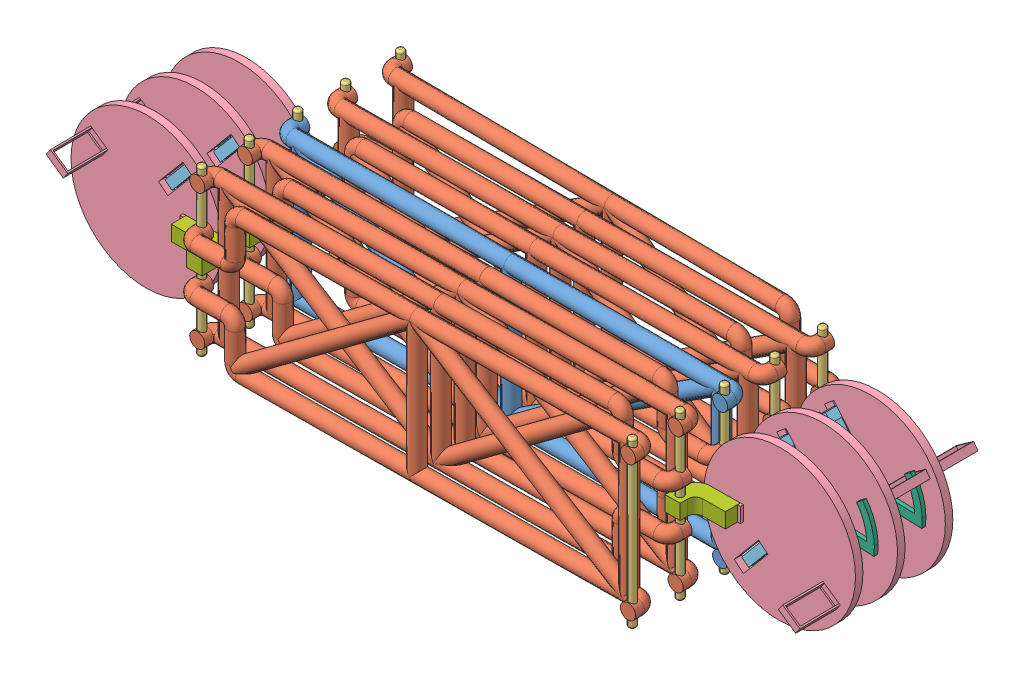
SolidWorks assembly assem3, configuration Default. Lengths in mm.
Overall size (502.87 110 155.14).
49 component instances, 7 part files, 55 mates.
Components (placement in the parent):
- center_frame-1: center_frame [Default] at (106.7449 154.0324 247.9449) size (310 100 22)
- true_frame-1: true_frame [Default] at (106.7528 154.6386 264.0904) x (-1 0 0.00097) z (-0.00097 0 -1) size (310 100 22)
- true_frame-2: true_frame [Default] at (106.7006 154.6386 231.153) x (0.999986 0 -0.00528) z (0.00528 0 0.999986) size (310 100 22)
- true_frame-3: true_frame [Default] at (106.6161 154.9393 215.1532) x (-0.999986 0 0.00528) z (0.00528 0 0.999986) size (310 100 22)
- true_frame-4: true_frame [Default] at (106.8233 154.9393 278.9571) x (0.999964 0 -0.008523) z (-0.008523 0 -0.999964) size (310 100 22)
- hinge_rod-1: hinge_rod [Default] at (256.7449 99.5924 255.9449) x (0.999788 0 -0.020583) z (0.020583 0 0.999788) size (5 110 5)
- hinge_rod-2: hinge_rod [Default] at (256.6563 99.5924 222.361) x (0.596438 0 -0.802659) z (0.802659 0 0.596438) size (5 110 5)
- hinge_rod-3: hinge_rod [Default] at (256.8861 99.5924 285.6784) x (0.825949 0 -0.563745) z (0.563745 0 0.825949) size (5 110 5)
- hinge_rod-4: hinge_rod [Default] at (-43.2394 99.5924 272.2358) x (0.395821 0 -0.918328) z (0.918328 0 0.395821) size (5 110 5)
- hinge_rod-5: hinge_rod [Default] at (-43.2551 99.5924 239.9449) x (0.565106 0 0.825018) z (-0.825018 0 0.565106) size (5 110 5)
- hinge_rod-6: hinge_rod [Default] at (-43.424 99.5924 207.9453) x (-0.435776 0 0.900055) z (-0.900055 0 -0.435776) size (5 110 5)
- Assem4^assem3-1: Assem4^assem3 [Default] at (0 -0.7838 0) size (106.16 100 39.17) (virtual)
  - Cap_base-1: Cap_base [Default] at (307.7348 155.7231 237.0915) x (0.999986 0 -0.00528) z (0.00528 0 0.999986) size (100 100 38)
  - Cap_lid-1: Cap_lid [Default] at (289.162 177.8597 239.4396) x (0.643702 -0.765268 -0.003399) z (-0.765258 -0.643711 0.004041) size (20 9.5 11)
  - Cap_pin-1: Cap_pin [Default] at (307.7902 155.7231 247.5914) x (0.999004 -0.044302 -0.005275) z (0.00528 0 0.999986) size (80 32.64 2.5)
  - lock_arm-1: lock_arm [Default] at (281.7351 160.7231 237.2288) x (-0.00528 0 -0.999986) z (-0.999986 0 0.00528) size (20 10 30)
- Assem4^assem3-2: Assem4^assem3 [Default] at (212.456 -0.7838 495.7011) x (-0.999991 0 -0.00431) z (0.00431 0 -0.999991) size (106.16 100 39.17) (virtual)
  - Cap_base-1: Cap_base [Default] at (307.7348 155.7231 237.0915) x (0.999986 0 -0.00528) z (0.00528 0 0.999986) size (100 100 38)
  - Cap_lid-1: Cap_lid [Default] at (289.162 177.8597 239.4396) x (0.643702 -0.765268 -0.003399) z (-0.765258 -0.643711 0.004041) size (20 9.5 11)
  - Cap_pin-1: Cap_pin [Default] at (307.7902 155.7231 247.5914) x (0.999004 -0.044302 -0.005275) z (0.00528 0 0.999986) size (80 32.64 2.5)
  - lock_arm-1: lock_arm [Default] at (281.7351 160.7231 237.2288) x (-0.00528 0 -0.999986) z (-0.999986 0 0.00528) size (20 10 30)
- true_frame-5: true_frame [Default] at (106.9597 154.6386 294.9565) x (-0.999964 0 0.008523) z (-0.008523 0 -0.999964) size (310 100 22)
- true_frame-6: true_frame [Default] at (107.0961 154.9393 310.956) x (0.999964 0 -0.008523) z (-0.008523 0 -0.999964) size (310 100 22)
- hinge_rod-7: hinge_rod [Default] at (-42.9667 99.5924 304.2347) x (0.864022 0 -0.503454) z (0.503454 0 0.864022) size (5 110 5)
- hinge_rod-8: hinge_rod [Default] at (257.1588 99.5924 317.6773) x (0.395821 0 -0.918328) z (0.918328 0 0.395821) size (5 110 5)
- Assem4^assem3-3: Assem4^assem3 [Default] at (214.4093 -0.7838 525.7623) x (-0.999995 0 0.003243) z (-0.003243 0 -0.999995) size (106.16 100 39.17) (virtual)
  - Cap_base-1: Cap_base [Default] at (307.7348 155.7231 237.0915) x (0.999986 0 -0.00528) z (0.00528 0 0.999986) size (100 100 38)
  - Cap_lid-1: Cap_lid [Default] at (289.162 177.8597 239.4396) x (0.643702 -0.765268 -0.003399) z (-0.765258 -0.643711 0.004041) size (20 9.5 11)
  - Cap_pin-1: Cap_pin [Default] at (307.7902 155.7231 247.5914) x (0.999004 -0.044302 -0.005275) z (0.00528 0 0.999986) size (80 32.64 2.5)
  - lock_arm-1: lock_arm [Default] at (281.7351 160.7231 237.2288) x (-0.00528 0 -0.999986) z (-0.999986 0 0.00528) size (20 10 30)
- Assem4^assem3-5: Assem4^assem3 [Default] at (3.3234 310.3617 511.5608) x (0.999905 0 -0.013803) z (-0.013803 0 -0.999905) size (106.16 100 39.17) (virtual)
  - Cap_base-1: Cap_base [Default] at (307.7348 155.7231 237.0915) x (0.999986 0 -0.00528) z (0.00528 0 0.999986) size (100 100 38)
  - Cap_lid-1: Cap_lid [Default] at (289.162 177.8597 239.4396) x (0.643702 -0.765268 -0.003399) z (-0.765258 -0.643711 0.004041) size (20 9.5 11)
  - Cap_pin-1: Cap_pin [Default] at (307.7902 155.7231 247.5914) x (0.999004 -0.044302 -0.005275) z (0.00528 0 0.999986) size (80 32.64 2.5)
  - lock_arm-1: lock_arm [Default] at (281.7351 160.7231 237.2288) x (-0.00528 0 -0.999986) z (-0.999986 0 0.00528) size (20 10 30)
- true_frame-7: true_frame [Default] at (106.5316 154.6386 199.1534) x (0.999986 0 -0.00528) z (0.00528 0 0.999986) size (310 100 22)
- true_frame-8: true_frame [Default] at (106.5712 154.9393 180.919) x (-0.999954 0 -0.009619) z (-0.009619 0 0.999954) size (310 100 22)
- hinge_rod-9: hinge_rod [Default] at (256.4873 99.5924 190.3615) x (-0.435776 0 0.900055) z (-0.900055 0 -0.435776) size (5 110 5)
- Assem4^assem3-6: Assem4^assem3 [Default] at (-0.169 -0.7837 -31.9996) size (106.16 100 39.17) (virtual)
  - Cap_base-1: Cap_base [Default] at (307.7348 155.7231 237.0915) x (0.999986 0 -0.00528) z (0.00528 0 0.999986) size (100 100 38)
  - Cap_lid-1: Cap_lid [Default] at (289.162 177.8597 239.4396) x (0.643702 -0.765268 -0.003399) z (-0.765258 -0.643711 0.004041) size (20 9.5 11)
  - Cap_pin-1: Cap_pin [Default] at (307.7902 155.7231 247.5914) x (0.999004 -0.044302 -0.005275) z (0.00528 0 0.999986) size (80 32.64 2.5)
  - lock_arm-1: lock_arm [Default] at (281.7351 160.7231 237.2288) x (-0.00528 0 -0.999986) z (-0.999986 0 0.00528) size (20 10 30)
- Assem4^assem3-7: Assem4^assem3 [Default] at (210.8697 310.3617 -17.1137) x (-0.999944 0 0.01056) z (0.01056 0 0.999944) size (106.16 100 39.17) (virtual)
  - Cap_base-1: Cap_base [Default] at (307.7348 155.7231 237.0915) x (0.999986 0 -0.00528) z (0.00528 0 0.999986) size (100 100 38)
  - Cap_lid-1: Cap_lid [Default] at (289.162 177.8597 239.4396) x (0.643702 -0.765268 -0.003399) z (-0.765258 -0.643711 0.004041) size (20 9.5 11)
  - Cap_pin-1: Cap_pin [Default] at (307.7902 155.7231 247.5914) x (0.999004 -0.044302 -0.005275) z (0.00528 0 0.999986) size (80 32.64 2.5)
  - lock_arm-1: lock_arm [Default] at (281.7351 160.7231 237.2288) x (-0.00528 0 -0.999986) z (-0.999986 0 0.00528) size (20 10 30)
- hinge_rod-10: hinge_rod [Default] at (-43.3449 99.5924 171.4765) x (-0.435776 0 0.900055) z (-0.900055 0 -0.435776) size (5 110 5)
Mates (geometry in assembly coordinates):
- Concentric1: concentric aligned: cylinder of center_frame-1 through (256.7449 104.0324 255.9449) axis (0 1 0) radius 2.5; cylinder of true_frame-1 through (256.7449 104.6386 255.9449) axis (0 1 0) radius 2.5
- Distance1: distance = 30 mm: point of center_frame-1; point of true_frame-1
- Concentric2: concentric aligned: cylinder of center_frame-1 through (-43.2551 104.0324 239.9449) axis (0 1 0) radius 2.5; cylinder of true_frame-2 through (-43.2551 104.6386 239.9449) axis (0 1 0) radius 2.5
- Distance3: distance = 30 mm: point of center_frame-1; point of true_frame-2
- Concentric3: concentric anti-aligned: cylinder of true_frame-2 through (256.6563 104.6386 222.361) axis (0 1 0) radius 2.5; cylinder of true_frame-3 through (256.6563 204.9393 222.361) axis (0 -1 0) radius 2.5
- Distance4: distance = 60 mm: point of true_frame-3; point of true_frame-2
- Concentric4: concentric anti-aligned: cylinder of true_frame-1 through (-43.2394 104.6386 272.2358) axis (0 1 0) radius 2.5; cylinder of true_frame-4 through (-43.2394 204.9393 272.2358) axis (0 -1 0) radius 2.5
- Distance5: distance = 60 mm: point of true_frame-1; point of true_frame-4
- Concentric5: concentric anti-aligned: cylinder of center_frame-1 through (256.7449 104.0324 255.9449) axis (0 1 0) radius 2.5; cylinder of hinge_rod-1 through (256.7449 209.5924 255.9449) axis (0 -1 0) radius 2.5
- Concentric6: concentric aligned: cylinder of true_frame-3 through (256.6563 204.9393 222.361) axis (0 -1 0) radius 2.5; cylinder of hinge_rod-2 through (256.6563 209.5924 222.361) axis (0 -1 0) radius 2.5
- Coincident7: coincident aligned: plane of hinge_rod-1 through (256.7449 209.5924 255.9449) normal (0 1 0); plane of hinge_rod-2 through (256.6563 209.5924 222.361) normal (0 1 0)
- Concentric7: concentric aligned: cylinder of true_frame-4 through (256.8861 204.9393 285.6784) axis (0 -1 0) radius 2.5; cylinder of hinge_rod-3 through (256.8861 209.5924 285.6784) axis (0 -1 0) radius 2.5
- Coincident8: coincident aligned: plane of hinge_rod-3 through (256.8861 209.5924 285.6784) normal (0 1 0); plane of hinge_rod-1 through (256.7449 209.5924 255.9449) normal (0 1 0)
- Coincident9: coincident aligned: plane of hinge_rod-3 through (256.8861 209.5924 285.6784) normal (0 1 0); plane of hinge_rod-2 through (256.6563 209.5924 222.361) normal (0 1 0)
- Concentric8: concentric aligned: cylinder of true_frame-4 through (-43.2394 204.9393 272.2358) axis (0 -1 0) radius 2.5; cylinder of hinge_rod-4 through (-43.2394 209.5924 272.2358) axis (0 -1 0) radius 2.5
- Concentric9: concentric anti-aligned: cylinder of true_frame-2 through (-43.2551 104.6386 239.9449) axis (0 1 0) radius 2.5; cylinder of hinge_rod-5 through (-43.2551 209.5924 239.9449) axis (0 -1 0) radius 2.5
- Concentric10: concentric aligned: cylinder of true_frame-3 through (-43.424 204.9393 207.9453) axis (0 -1 0) radius 2.5; cylinder of hinge_rod-6 through (-43.424 209.5924 207.9453) axis (0 -1 0) radius 2.5
- Coincident14: coincident aligned: plane of hinge_rod-6 through (-43.424 209.5924 207.9453) normal (0 1 0); plane of hinge_rod-5 through (-43.2551 209.5924 239.9449) normal (0 1 0)
- Coincident15: coincident aligned: plane of hinge_rod-6 through (-43.424 209.5924 207.9453) normal (0 1 0); plane of hinge_rod-4 through (-43.2394 209.5924 272.2358) normal (0 1 0)
- Coincident16: coincident aligned: plane of hinge_rod-6 through (-43.424 209.5924 207.9453) normal (0 1 0); plane of hinge_rod-2 through (256.6563 209.5924 222.361) normal (0 1 0)
- Coincident17: coincident aligned: plane of hinge_rod-6 through (-43.424 209.5924 207.9453) normal (0 1 0); plane of hinge_rod-1 through (256.7449 209.5924 255.9449) normal (0 1 0)
- Coincident18: coincident aligned: plane of hinge_rod-6 through (-43.424 209.5924 207.9453) normal (0 1 0); plane of hinge_rod-3 through (256.8861 209.5924 285.6784) normal (0 1 0)
- Concentric20: concentric aligned: cylinder of hinge_rod-2 through (256.6563 209.5924 222.361) axis (0 -1 0) radius 2.5; cylinder of Assem4^assem3-1/lock_arm-1 through (256.6563 159.9393 222.361) axis (0 -1 0) radius 2.5
- Parallel8: parallel aligned: plane of true_frame-2 through (256.6404 109.6386 219.3611) normal (-0.00528 0 -0.999986); plane of Assem4^assem3-1/lock_arm-1 through (281.6295 149.9393 217.2291) normal (-0.00528 0 -0.999986)
- Distance12: distance = 17 mm: point of true_frame-3; point of Assem4^assem3-1/lock_arm-1
- Concentric21: concentric aligned: cylinder of hinge_rod-4 through (-43.2394 209.5924 272.2358) axis (0 -1 0) radius 2.5; cylinder of Assem4^assem3-2/lock_arm-1 through (-43.2394 159.9393 272.2358) axis (0 -1 0) radius 2.5
- Parallel9: parallel aligned: plane of true_frame-1 through (-43.2365 199.6386 275.2358) normal (0.00097 0 1); plane of Assem4^assem3-2/lock_arm-1 through (-68.2345 149.9393 277.2601) normal (0.00097 0 1)
- Distance13: distance = 17 mm: point of true_frame-4; point of Assem4^assem3-2/lock_arm-1
- Concentric22: concentric anti-aligned: cylinder of hinge_rod-3 through (256.8861 209.5924 285.6784) axis (0 -1 0) radius 2.5; cylinder of true_frame-5 through (256.8861 104.6386 285.6784) axis (0 1 0) radius 2.5
- Distance14: distance = 60 mm: point of true_frame-5; point of true_frame-4
- Concentric23: concentric anti-aligned: cylinder of true_frame-5 through (-42.9667 104.6386 304.2347) axis (0 1 0) radius 2.5; cylinder of hinge_rod-7 through (-42.9667 209.5924 304.2347) axis (0 -1 0) radius 2.5
- Concentric24: concentric aligned: cylinder of true_frame-6 through (-42.9667 204.9393 304.2347) axis (0 -1 0) radius 2.5; cylinder of hinge_rod-7 through (-42.9667 209.5924 304.2347) axis (0 -1 0) radius 2.5
- Coincident33: coincident aligned: plane of hinge_rod-4 through (-43.2394 209.5924 272.2358) normal (0 1 0); plane of hinge_rod-7 through (-42.9667 209.5924 304.2347) normal (0 1 0)
- Distance15: distance = 60 mm: point of true_frame-5; point of true_frame-6
- Concentric25: concentric aligned: cylinder of true_frame-6 through (257.1588 204.9393 317.6773) axis (0 -1 0) radius 2.5; cylinder of hinge_rod-8 through (257.1588 209.5924 317.6773) axis (0 -1 0) radius 2.5
- Coincident34: coincident aligned: plane of hinge_rod-3 through (256.8861 209.5924 285.6784) normal (0 1 0); plane of hinge_rod-8 through (257.1588 209.5924 317.6773) normal (0 1 0)
- Concentric26: concentric aligned: cylinder of hinge_rod-7 through (-42.9667 209.5924 304.2347) axis (0 -1 0) radius 2.5; cylinder of Assem4^assem3-3/lock_arm-1 through (-42.9667 159.9393 304.2347) axis (0 -1 0) radius 2.5
- Distance17: distance = 17 mm: point of true_frame-6; point of Assem4^assem3-3/lock_arm-1
- Parallel10: parallel aligned: plane of true_frame-5 through (-42.9411 199.6386 307.2346) normal (0.008523 0 0.999964); plane of Assem4^assem3-3/lock_arm-1 through (-67.9231 149.9393 309.4476) normal (0.008523 0 0.999964)
- Concentric28: concentric anti-aligned: cylinder of hinge_rod-3 through (256.8861 209.5924 285.6784) axis (0 -1 0) radius 2.5; cylinder of Assem4^assem3-5/lock_arm-1 through (256.8861 149.6386 285.6784) axis (0 1 0) radius 2.5
- Parallel11: parallel aligned: plane of true_frame-4 through (256.9116 199.9393 288.6783) normal (0.008523 0 0.999964); plane of Assem4^assem3-5/lock_arm-1 through (281.9278 159.6386 290.4652) normal (0.008523 0 0.999964)
- Distance18: distance = 17 mm: point of Assem4^assem3-5/lock_arm-1; point of true_frame-5
- Concentric29: concentric anti-aligned: cylinder of hinge_rod-6 through (-43.424 209.5924 207.9453) axis (0 -1 0) radius 2.5; cylinder of true_frame-7 through (-43.424 104.6386 207.9453) axis (0 1 0) radius 2.5
- Concentric30: concentric anti-aligned: cylinder of true_frame-7 through (256.4873 104.6386 190.3615) axis (0 1 0) radius 2.5; cylinder of hinge_rod-9 through (256.4873 209.5924 190.3615) axis (0 -1 0) radius 2.5
- Concentric31: concentric aligned: cylinder of true_frame-8 through (256.4873 204.9393 190.3615) axis (0 -1 0) radius 2.5; cylinder of hinge_rod-9 through (256.4873 209.5924 190.3615) axis (0 -1 0) radius 2.5
- Distance19: distance = 60 mm: point of true_frame-7; point of true_frame-3
- Coincident37: coincident aligned: circle of hinge_rod-2; plane of hinge_rod-9 through (256.4873 209.5924 190.3615) normal (0 1 0)
- Concentric33: concentric aligned: cylinder of hinge_rod-9 through (256.4873 209.5924 190.3615) axis (0 -1 0) radius 2.5; cylinder of Assem4^assem3-6/lock_arm-1 through (256.4873 159.9394 190.3615) axis (0 -1 0) radius 2.5
- Distance22: distance = 17 mm: point of Assem4^assem3-6/lock_arm-1; point of true_frame-8
- Distance23: distance = 60 mm: point of true_frame-8; point of true_frame-7
- Concentric34: concentric anti-aligned: cylinder of hinge_rod-6 through (-43.424 209.5924 207.9453) axis (0 -1 0) radius 2.5; cylinder of Assem4^assem3-7/lock_arm-1 through (-43.424 149.6386 207.9453) axis (0 1 0) radius 2.5
- Parallel12: parallel aligned: plane of true_frame-3 through (-43.4399 199.9393 204.9454) normal (-0.00528 0 -0.999986); plane of Assem4^assem3-7/lock_arm-1 through (-68.4501 159.6386 203.0774) normal (-0.00528 0 -0.999986)
- Distance25: distance = 17 mm: point of Assem4^assem3-7/lock_arm-1; point of true_frame-7
- Concentric35: concentric aligned: cylinder of true_frame-8 through (-43.3449 204.9393 171.4765) axis (0 -1 0) radius 2.5; cylinder of hinge_rod-10 through (-43.3449 209.5924 171.4765) axis (0 -1 0) radius 2.5
- Coincident40: coincident aligned: plane of hinge_rod-6 through (-43.424 209.5924 207.9453) normal (0 1 0); plane of hinge_rod-10 through (-43.3449 209.5924 171.4765) normal (0 1 0)
